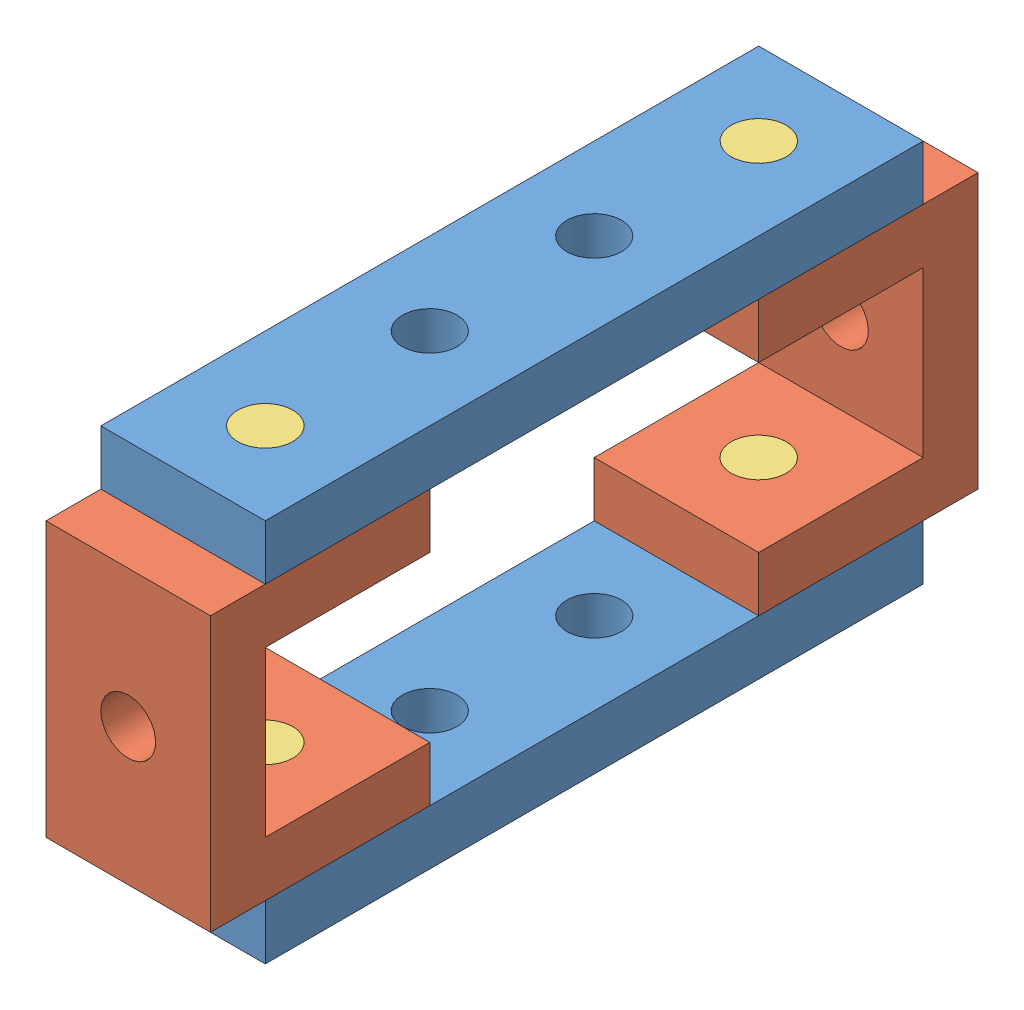
SolidWorks assembly Assembly, configuration Default. Lengths in mm.
Overall size (30 70 140).
8 component instances, 3 part files, 21 mates.
Components (placement in the parent):
- Plate, Quad-1: Plate, Quad [Default] at (0 -10 0) x (0 0 1) z (0 1 0) size (120 30 10)
- C-Bracket-1: C-Bracket [Default] at (0 0 30) size (30 50 40)
- C-Bracket-2: C-Bracket [Default] at (30 0 90) x (-1 0 0) z (0 0 -1) size (30 50 40)
- Plate, Quad-2: Plate, Quad [Default] at (30 60 0) x (0 0 1) z (0 -1 0) size (120 30 10)
- PG20-1-1: PG20-1 [Default] at (15 40 105) x (1 0 0) z (0 1 0) size (10 10 20)
- PG20-1-2: PG20-1 [Default] at (15 40 15) x (1 0 0) z (0 1 0) size (10 10 20)
- PG20-1-3: PG20-1 [Default] at (15 10 105) x (1 0 0) z (0 -1 0) size (10 10 20)
- PG20-1-4: PG20-1 [Default] at (15 10 15) x (1 0 0) z (0 -1 0) size (10 10 20)
Mates (geometry in assembly coordinates):
- Coincident2: coincident: point of Plate, Quad-1
- Parallel1: parallel anti-aligned: plane of Plate, Quad-1 through (0 -10 0) normal (0 -1 0)
- Coincident4: coincident anti-aligned: plane of Plate, Quad-1 through (0 0 0) normal (-1 0 0)
- Concentric1: concentric anti-aligned: cylinder of Plate, Quad-1 through (15 0 15) axis (0 -1 0) radius 5; cylinder of PG20-1-4 through (15 -10 15) axis (0 1 0) radius 5
- Coincident6: coincident aligned: plane of Plate, Quad-1 through (0 -10 0) normal (0 -1 0); plane of PG20-1-4 through (15 -10 15) normal (0 -1 0)
- Concentric2: concentric anti-aligned: cylinder of Plate, Quad-1 through (15 0 105) axis (0 -1 0) radius 5; cylinder of PG20-1-3 through (15 -10 105) axis (0 1 0) radius 5
- Coincident7: coincident aligned: plane of Plate, Quad-1 through (0 -10 0) normal (0 -1 0); plane of PG20-1-3 through (15 -10 105) normal (0 -1 0)
- Concentric3: concentric aligned: cylinder of C-Bracket-1 through (15 -16 15) axis (0 1 0) radius 5; cylinder of PG20-1-4 through (15 -10 15) axis (0 1 0) radius 5
- Coincident9: coincident aligned: plane of C-Bracket-1 through (30 10 0) normal (0 1 0); plane of PG20-1-4 through (15 10 15) normal (0 1 0)
- Coincident10: coincident aligned: plane of Plate, Quad-1 through (0 0 0) normal (-1 0 0); plane of C-Bracket-1 through (0 0 30) normal (-1 0 0)
- Concentric4: concentric anti-aligned: cylinder of C-Bracket-1 through (15 -16 15) axis (0 1 0) radius 5; cylinder of PG20-1-2 through (15 60 15) axis (0 -1 0) radius 5
- Coincident11: coincident aligned: plane of C-Bracket-1 through (30 40 30) normal (0 -1 0); plane of PG20-1-2 through (15 40 15) normal (0 -1 0)
- Coincident12: coincident anti-aligned: plane of C-Bracket-1 through (30 50 -10) normal (0 1 0); plane of Plate, Quad-2 through (0 50 0) normal (0 -1 0)
- Concentric5: concentric anti-aligned: cylinder of Plate, Quad-2 through (15 50 15) axis (0 1 0) radius 5; cylinder of PG20-1-2 through (15 60 15) axis (0 -1 0) radius 5
- Concentric7: concentric aligned: cylinder of C-Bracket-2 through (15 -16 105) axis (0 1 0) radius 5; cylinder of PG20-1-3 through (15 -10 105) axis (0 1 0) radius 5
- Coincident13: coincident aligned: plane of C-Bracket-2 through (0 10 120) normal (0 1 0); plane of PG20-1-3 through (15 10 105) normal (0 1 0)
- Coincident15: coincident aligned: plane of Plate, Quad-1 through (0 0 0) normal (-1 0 0); plane of C-Bracket-2 through (0 0 90) normal (-1 0 0)
- Concentric8: concentric: cylinder of C-Bracket-2 through (15 -16 105) axis (0 1 0) radius 5; cylinder of PG20-1-1 through (15 60 105) axis (0 -1 0) radius 5
- Coincident16: coincident: plane of C-Bracket-2 through (0 40 90) normal (0 -1 0); plane of PG20-1-1 through (15 40 105) normal (0 -1 0)
- Concentric9: concentric: cylinder of Plate, Quad-2 through (15 50 105) axis (0 1 0) radius 5; cylinder of PG20-1-1 through (15 60 105) axis (0 -1 0) radius 5
- Coincident17: coincident aligned: plane of Plate, Quad-2 through (30 60 0) normal (0 1 0); plane of PG20-1-1 through (15 60 105) normal (0 1 0)
